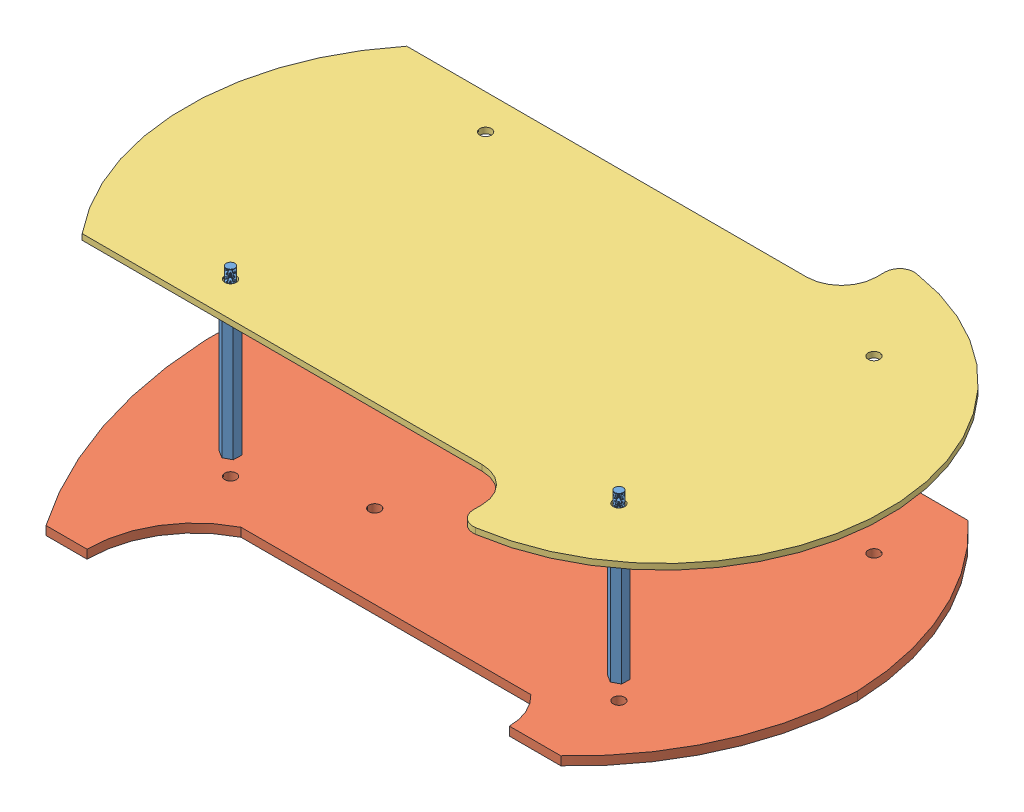
SolidWorks assembly albert_soerjonoto_assembly, configuration Default. Lengths in mm.
Overall size (241.29 65.95 180).
4 component instances, 3 part files, 3 mates.
Components (placement in the parent):
- albert_soerjonoto_M3_spacer_drawing-1: albert_soerjonoto_M3_spacer_drawing [Default] at (-143.321 29.2547 415.8291) size (5.1 56 5.77)
- albert_soerjonoto_top_frame-1: albert_soerjonoto_top_frame [Default] at (-75.492 19.3031 372.3384) x (-1 0 0) z (0 0 -1) size (217.53 3 180)
- albert_soerjonoto_chassis_frame-2: albert_soerjonoto_chassis_frame [Default] at (-76.321 81.2547 371.8291) x (1 0 0) z (0 -1 0) size (241.29 152.11 2)
- albert_soerjonoto_M3_spacer_drawing-2: albert_soerjonoto_M3_spacer_drawing [Default] at (-9.321 29.2547 415.8291) size (5.1 56 5.77)
Mates (geometry in assembly coordinates):
- Concentric1: concentric anti-aligned: circle of albert_soerjonoto_M3_spacer_drawing-1; circle of albert_soerjonoto_chassis_frame-2
- Concentric3: concentric anti-aligned: circle of albert_soerjonoto_chassis_frame-2; circle of albert_soerjonoto_M3_spacer_drawing-2
- Concentric4: concentric anti-aligned: circle of albert_soerjonoto_top_frame-1; circle of albert_soerjonoto_M3_spacer_drawing-2
